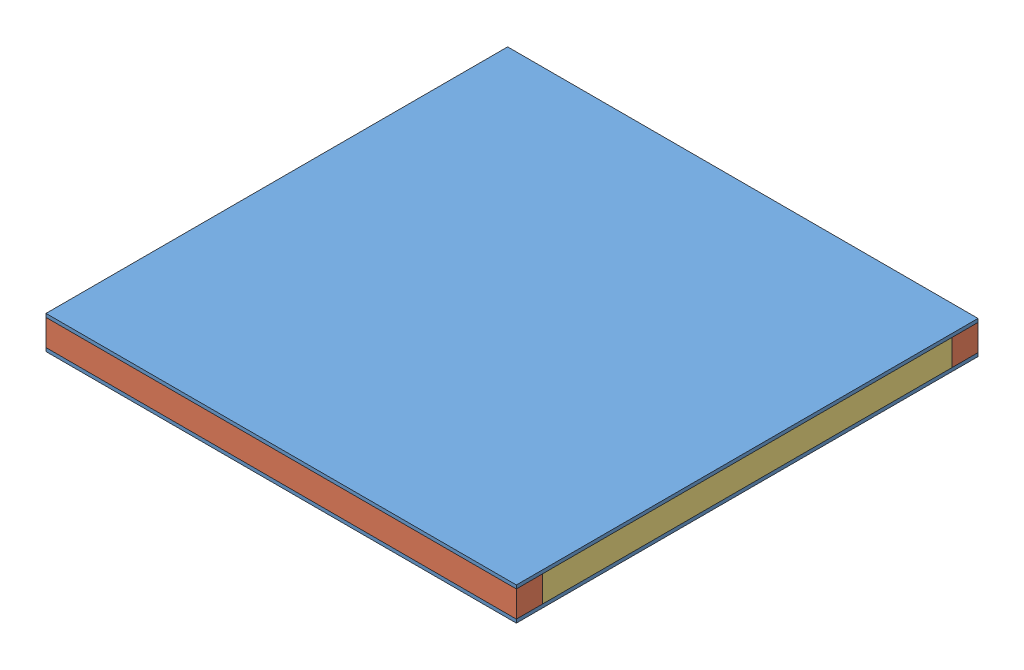
SolidWorks assembly generator_side_wall, configuration Default. Lengths in mm.
Overall size (685.8 48.26 673.1).
10 component instances, 4 part files, 19 mates.
Components (placement in the parent):
- generator_side_wall_plywood-1: generator_side_wall_plywood [Default] at (-62.1033 594.2973 533.651) size (685.8 5.08 673.1)
- 2x2_side_wall_length-1: 2x2_side_wall_length [Default] at (-62.1033 637.4773 1168.651) x (0 -1 0) z (0 0 1) size (38.1 685.8 38.1)
- 2x2_side_wall_length-2: 2x2_side_wall_length [Default] at (-62.1033 637.4773 533.651) x (0 -1 0) z (0 0 1) size (38.1 685.8 38.1)
- 2x2_side_wall_height-1: 2x2_side_wall_height [Default] at (-62.1033 599.3773 533.651) x (1 0 0) z (0 1 0) size (38.1 596.9 38.1)
- 2x2_side_wall_height-2: 2x2_side_wall_height [Default] at (-709.8033 599.3773 533.651) x (1 0 0) z (0 1 0) size (38.1 596.9 38.1)
- acoustic_foam_12x12-1: acoustic_foam_12x12 [Default] at (280.7967 599.3773 863.851) size (304.8 38.1 304.8)
- acoustic_foam_12x12-2: acoustic_foam_12x12 [Default] at (-24.0033 599.3773 863.851) size (304.8 38.1 304.8)
- acoustic_foam_12x12-3: acoustic_foam_12x12 [Default] at (280.7967 599.3773 559.051) size (304.8 38.1 304.8)
- acoustic_foam_12x12-4: acoustic_foam_12x12 [Default] at (-24.0033 599.3773 559.051) size (304.8 38.1 304.8)
- generator_side_wall_plywood-2: generator_side_wall_plywood [Default] at (-62.1033 637.4773 533.651) size (685.8 5.08 673.1)
Mates (geometry in assembly coordinates):
- Coincident1: coincident: plane of generator_side_wall_plywood-1 through (-62.1033 599.3773 533.651) normal (0 1 0); plane of 2x2_side_wall_length-1 through (623.6967 599.3773 1168.651) normal (0 -1 0)
- Coincident2: coincident: plane of generator_side_wall_plywood-1 through (623.6967 599.3773 533.651) normal (1 0 0); plane of 2x2_side_wall_length-1 through (623.6967 637.4773 1168.651) normal (1 0 0)
- Coincident3: coincident: plane of generator_side_wall_plywood-1 through (-62.1033 599.3773 1206.751) normal (0 0 1); plane of 2x2_side_wall_length-1 through (623.6967 637.4773 1206.751) normal (0 0 1)
- Coincident4: coincident: plane of generator_side_wall_plywood-1 through (-62.1033 599.3773 533.651) normal (0 1 0); plane of 2x2_side_wall_length-2 through (623.6967 599.3773 533.651) normal (0 -1 0)
- Coincident5: coincident: plane of 2x2_side_wall_length-1 through (623.6967 637.4773 1168.651) normal (1 0 0); plane of 2x2_side_wall_length-2 through (623.6967 637.4773 533.651) normal (1 0 0)
- Coincident6: coincident: plane of generator_side_wall_plywood-1 through (-62.1033 599.3773 533.651) normal (0 0 -1); plane of 2x2_side_wall_length-2 through (623.6967 637.4773 533.651) normal (0 0 -1)
- InPlace1: in place: plane of generator_side_wall_plywood-1 through (-62.1033 599.3773 533.651) normal (0 1 0); plane of ? through (0 599.3773 0) normal (0 1 0); moOrthogonalPlaneRef_w of generator_side_wall_plywood-1 through (-62.1033 599.3773 533.651) normal (0 1 0); plane of ? through (0 599.3773 0) normal (0 0 -1); plane of generator_side_wall_plywood-1 through (-62.1033 599.3773 533.651) normal (0 1 0); plane of ? through (0 599.3773 0) normal (1 0 0); plane of generator_side_wall_plywood-1 through (-62.1033 599.3773 533.651) normal (0 1 0); unknown of 2x2_side_wall_height-1
- Coincident7: coincident: plane of generator_side_wall_plywood-1; plane of 2x2_side_wall_height-1
- Coincident8: coincident: moOrthogonalPlaneRef_w of generator_side_wall_plywood-1 through (-62.1033 599.3773 533.651) normal (0 0 -1); plane of 2x2_side_wall_height-1 through (-62.1033 599.3773 533.651) normal (0 0 -1)
- Coincident9: coincident: moOrthogonalPlaneRef_w of generator_side_wall_plywood-1 through (-62.1033 599.3773 533.651) normal (-1 0 0); plane of 2x2_side_wall_height-1 through (-62.1033 599.3773 533.651) normal (1 0 0)
- Coincident10: coincident: plane of 2x2_side_wall_length-2 through (623.6967 637.4773 571.751) normal (0 0 1); plane of 2x2_side_wall_height-2 through (-24.0033 637.4773 571.751) normal (0 0 -1)
- Coincident11: coincident: plane of generator_side_wall_plywood-1 through (-62.1033 599.3773 533.651) normal (0 1 0); plane of 2x2_side_wall_height-2 through (-709.8033 599.3773 533.651) normal (0 -1 0)
- Coincident12: coincident: plane of 2x2_side_wall_length-1 through (-62.1033 637.4773 1168.651) normal (-1 0 0); plane of 2x2_side_wall_height-2 through (-62.1033 637.4773 571.751) normal (-1 0 0)
- Coincident13: coincident: plane of generator_side_wall_plywood-1 through (-62.1033 599.3773 533.651) normal (0 1 0); plane of acoustic_foam_12x12-1 through (280.7967 599.3773 863.851) normal (0 -1 0)
- Coincident14: coincident: plane of 2x2_side_wall_height-1 through (585.5967 637.4773 571.751) normal (-1 0 0); plane of acoustic_foam_12x12-1 through (585.5967 637.4773 863.851) normal (1 0 0)
- Coincident15: coincident: plane of 2x2_side_wall_length-1 through (623.6967 637.4773 1168.651) normal (0 0 -1); plane of acoustic_foam_12x12-1 through (280.7967 637.4773 1168.651) normal (0 0 1)
- Coincident17: coincident: plane of 2x2_side_wall_length-2 through (623.6967 637.4773 533.651) normal (0 1 0); plane of generator_side_wall_plywood-2 through (-62.1033 637.4773 533.651) normal (0 -1 0)
- Coincident18: coincident: plane of 2x2_side_wall_height-1 through (623.6967 637.4773 571.751) normal (1 0 0); plane of generator_side_wall_plywood-2 through (623.6967 642.5573 533.651) normal (1 0 0)
- Coincident19: coincident: plane of 2x2_side_wall_length-2 through (623.6967 637.4773 533.651) normal (0 0 -1); plane of generator_side_wall_plywood-2 through (-62.1033 642.5573 533.651) normal (0 0 -1)
